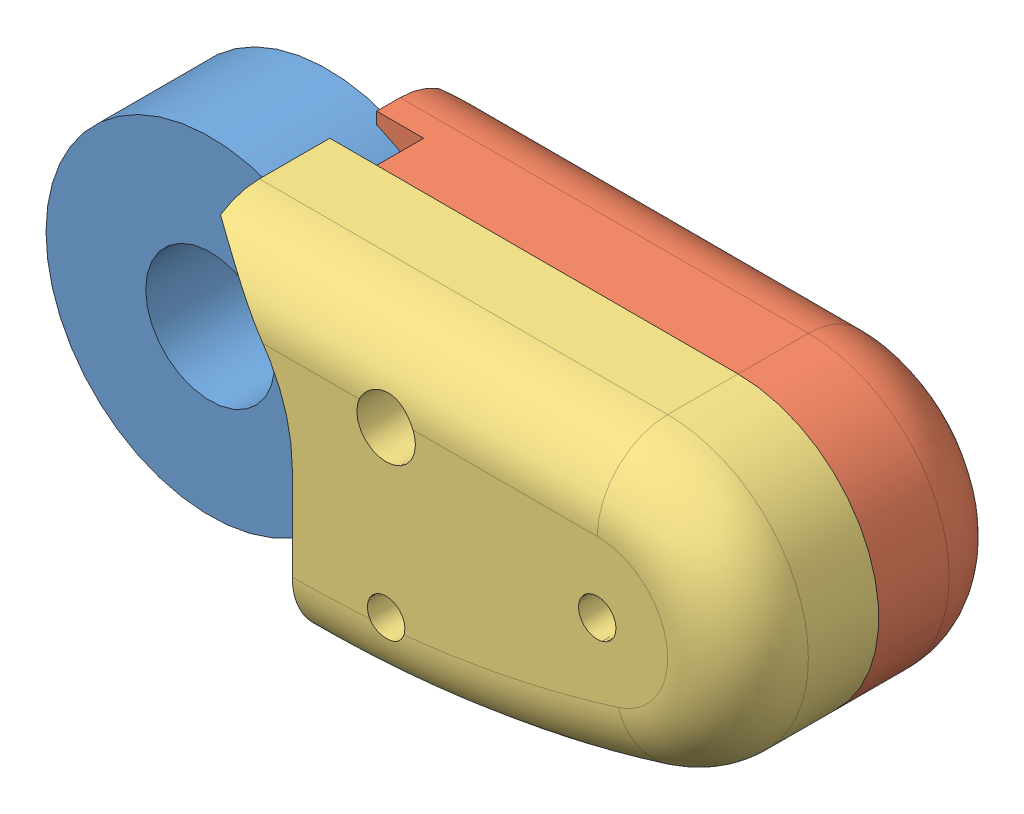
SolidWorks assembly fingerD-assembly, configuration Default. Lengths in mm.
Overall size (33 14.19 12.52).
3 component instances, 3 part files, 6 mates.
Components (placement in the parent):
- fingerD-middle-2: fingerD-middle [Default] at (-18.1975 -2.6168 16.0859) size (23 14 5)
- fingerD-left-2: fingerD-left [Default] at (-11.7414 11.5369 12.5859) size (23.4 14.19 6.17)
- fingerD-right-2: fingerD-right [Default] at (-11.7414 11.5369 18.5859) size (23.4 14.19 6.35)
Mates (geometry in assembly coordinates):
- Concentric2: concentric aligned: cylinder of fingerD-middle-2 through (-0.7414 15.0369 21.0859) axis (0 0 -1) radius 0.8; cylinder of fingerD-left-2 through (-0.7414 15.0369 18.5859) axis (0 0 -1) radius 0.8
- Concentric3: concentric aligned: cylinder of fingerD-middle-2 through (-0.7414 8.0369 21.0859) axis (0 0 -1) radius 0.8; cylinder of fingerD-left-2 through (-0.7414 8.0369 18.5859) axis (0 0 -1) radius 0.8
- Distance2: distance = 0.2 mm anti-aligned: plane of fingerD-middle-2 through (-18.1975 -2.6168 16.0859) normal (0 0 -1); plane of fingerD-left-2 through (-11.7414 11.5369 15.8859) normal (0 0 1)
- Concentric4: concentric aligned: cylinder of fingerD-middle-2 through (-0.7414 15.0369 21.0859) axis (0 0 -1) radius 0.8; cylinder of fingerD-right-2 through (-0.7414 15.0369 24.5859) axis (0 0 -1) radius 0.8
- Concentric5: concentric aligned: cylinder of fingerD-middle-2 through (-0.7414 8.0369 21.0859) axis (0 0 -1) radius 0.8; cylinder of fingerD-right-2 through (-0.7414 8.0369 24.5859) axis (0 0 -1) radius 0.8
- Distance1: distance = 0.2 mm anti-aligned: plane of fingerD-right-2 through (-11.7414 11.5369 21.2859) normal (0 0 -1); plane of fingerD-middle-2 through (-18.1975 -2.6168 21.0859) normal (0 0 1)
